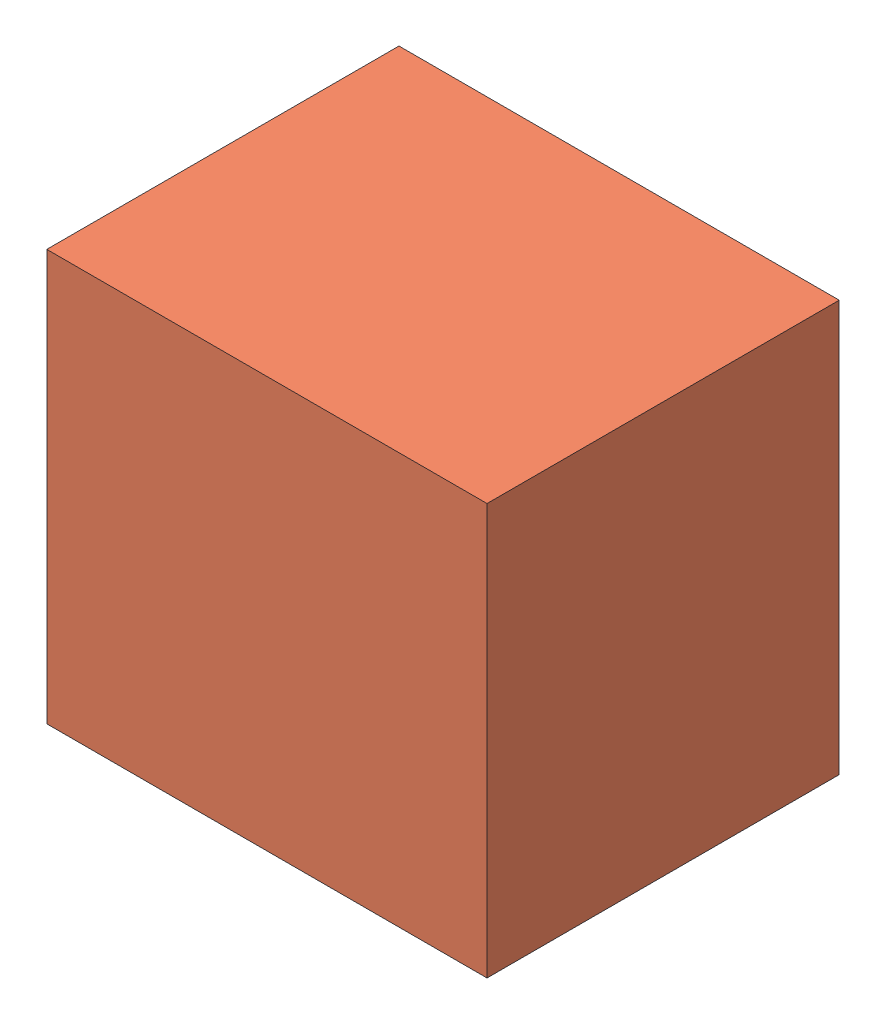
SolidWorks assembly Assem1, configuration Default. Lengths in mm.
Overall size (75 70 60).
2 component instances, 2 part files, 3 mates.
Components (placement in the parent):
- Curved Mold - 1-1: Curved Mold - 1 [Default] at (23.467 -57 4.2269) x (0.999915 0 0.013051) z (-0.013051 0 0.999915) size (64.34 55.9 51.11)
- Curved Mold - Negative - 1-1: Curved Mold - Negative - 1 [Default] at (0 -70 49.9463) x (1 0 0) z (0 1 0) size (75 60 70)
Mates (geometry in assembly coordinates):
- Distance1: distance = 5 mm aligned: plane of Curved Mold - 1-1 through (50.5681 -65 -0.4198) normal (0 -1 0); plane of Curved Mold - Negative - 1-1 through (0 -70 49.9463) normal (0 -1 0)
- Coincident2: coincident anti-aligned: plane of Curved Mold - Negative - 1-1 through (0 0 49.9463) normal (-1 0 0)
- Coincident3: coincident aligned: plane of Curved Mold - Negative - 1-1 through (0 0 49.9463) normal (0 1 0)
